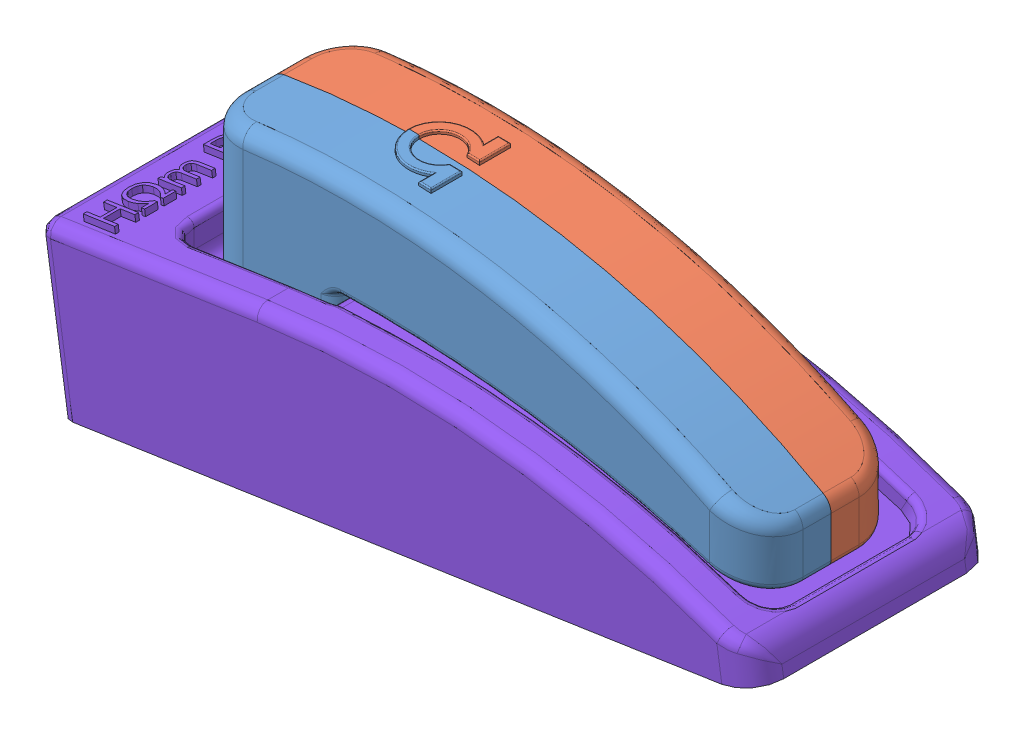
SolidWorks assembly final_assem, configuration Default. Lengths in mm.
Overall size (291.75 123.1 101.57).
10 component instances, 8 part files, 27 mates.
Components (placement in the parent):
- P8_right-1: P8_right [Default] at origin size (228.6 69.96 31.73)
- P8_left-1: P8_left [Default] at origin size (228.6 69.83 31.64)
- P1Speaker-1: P1Speaker [Default] at (29.1359 6.0917 30.5) x (0.999303 0.037323 0) z (-0.037323 0.999303 0) size (28 28 5.2)
- P1Inductor-1: P1Inductor [Default] at (29.0706 7.8405 30.5) x (0.999303 0.037323 0) z (0.037323 -0.999303 0) size (38.7 38.7 1.75)
- P1Keypad-2: P1Keypad [Default] at (121.818 36.3431 19.9085) x (0 0 1) z (-0.105093 -0.994462 0) size (51 64 15.68)
- button cap-1: button cap [Default] at (150.588 21.5839 47.6945) x (0.995909 -0.090357 0) z (0 0 1) size (10 5 10)
- button cap-2: button cap [Default] at (150.588 21.5839 24.3055) x (0.995909 -0.090357 0) z (0 0 1) size (10 5 10)
- led-1: led [Default] at (63.3042 28.0471 20.5) x (0.608948 -0.055249 -0.791284) z (-0.788047 0.071498 -0.611449) size (5 10.28 5)
- led-2: led [Default] at (63.3042 28.0471 40.5) x (-0.341202 0.030957 0.93948) z (0.935637 -0.084889 0.342604) size (5 10.28 5)
- Basepic-2: Basepic [Default] at (-2.8104 -2.6942 107.8186) x (1 0.000823 0) z (0 0 1) size (291.68 82.86 101.57)
Mates (geometry in assembly coordinates):
- Concentric1: concentric aligned: circle of P1Speaker-1; circle of P1Inductor-1
- Concentric2: concentric anti-aligned: circle of P8_right-1; circle of P1Speaker-1
- Coincident1: coincident: line of P8_right-1 through (36.7506 6.3761 31.5401) axis (0.999303 0.037323 0); plane of P1Inductor-1 through (29.1359 6.0917 30.5) normal (0.037323 -0.999303 0)
- Coincident2: coincident: line of P8_right-1 through (36.7506 6.3761 31.5401) axis (0.999303 0.037323 0); plane of P1Speaker-1 through (29.1359 6.0917 30.5) normal (0.037323 -0.999303 0)
- Concentric3: concentric aligned: cylinder of P8_right-1 through (6.35 55.6925 61) axis (0 0 -1) radius 6.35; cylinder of P8_left-1 through (6.35 55.6925 61) axis (0 0 -1) radius 6.35
- Concentric4: concentric aligned: cylinder of P8_right-1 through (226.06 1.7839 61) axis (0 0 -1) radius 2.54; cylinder of P8_left-1 through (226.06 1.7839 61) axis (0 0 -1) radius 2.54
- Coincident13: coincident: plane of P8_right-1 through (76.7043 40.1051 4.3119) normal (0.994462 -0.105093 0); line of P1Keypad-2 through (76.2839 36.1273 54.95) axis (0 0 -1)
- Coincident14: coincident: line of P8_right-1 through (138.2601 29.5777 30.5) axis (0.994462 -0.105093 0); plane of P1Keypad-2 through (121.2926 31.3708 19.9085) normal (-0.105093 -0.994462 0)
- Coincident15: coincident: line of P8_right-1 through (76.2839 36.1273 30.5) axis (0.994462 -0.105093 0); plane of P1Keypad-2 through (121.2926 31.3708 19.9085) normal (-0.105093 -0.994462 0)
- Coincident16: coincident: line of P8_right-1 through (81.5518 35.5706 54.6372) axis (0.994462 -0.105093 0.001005); plane of P1Keypad-2 through (121.2926 31.3708 19.9085) normal (-0.105093 -0.994462 0)
- Coincident17: coincident: plane of P8_right-1 through (0 -1.6705 30.5) normal (0 0 -1); moEndPointRef_w of P1Keypad-2
- Coincident18: coincident: plane of P8_right-1 through (0 -1.6705 30.5) normal (0 0 -1); moEndPointRef_w of P8_left-1
- Coincident19: coincident anti-aligned: plane of P8_right-1 through (151.1301 27.5593 47.6945) normal (0.995909 -0.090357 0); plane of button cap-1 through (151.0398 26.5634 47.6945) normal (-0.995909 0.090357 0)
- Coincident20: coincident anti-aligned: plane of P8_right-1 through (151.1301 27.5593 47.6945) normal (0 0 -1); plane of button cap-1 through (151.0398 26.5634 47.6945) normal (0 0 1)
- Distance1: distance = 2 mm aligned: plane of P8_right-1 through (3.3525 36.9505 0) normal (-0.090357 -0.995909 0); plane of button cap-1 through (150.588 21.5839 47.6945) normal (-0.090357 -0.995909 0)
- Coincident22: coincident anti-aligned: plane of P8_left-1 through (151.1301 27.5593 24.3055) normal (0 0 -1); plane of button cap-2 through (151.0398 26.5634 24.3055) normal (0 0 1)
- Coincident23: coincident anti-aligned: plane of P8_left-1 through (151.1301 27.5593 13.3055) normal (0.995909 -0.090357 0); plane of button cap-2 through (151.0398 26.5634 24.3055) normal (-0.995909 0.090357 0)
- Distance2: distance = 2 mm aligned: plane of button cap-2 through (150.588 21.5839 24.3055) normal (-0.090357 -0.995909 0); plane of P8_left-1 through (3.3525 36.9505 0) normal (-0.090357 -0.995909 0)
- Concentric5: concentric anti-aligned: cylinder of P8_left-1 through (60.1131 -7.1245 20.5) axis (0.090357 0.995909 0) radius 3; cylinder of led-1 through (63.0783 25.5573 20.5) axis (-0.090357 -0.995909 0) radius 2.5
- Tangent9: tangent anti-aligned: cylinder of P8_left-1 through (71.3027 -439.1129 61) axis (0 0 -1) radius 464.7284; sphere of led-1
- Concentric11: concentric anti-aligned: cylinder of P8_right-1 through (60.1131 -7.1245 40.5) axis (0.090357 0.995909 0) radius 3; cylinder of led-2 through (63.0783 25.5573 40.5) axis (-0.090357 -0.995909 0) radius 2.5
- Tangent10: tangent anti-aligned: cylinder of P8_right-1 through (71.3027 -439.1129 61) axis (0 0 -1) radius 464.7284; sphere of led-2
- Coincident26: coincident: plane of P8_right-1 through (0 -1.6705 30.5) normal (0 0 -1); moEndPointRef_w of Basepic-2
- Coincident27: coincident: plane of P8_right-1 through (0 -1.6705 30.5) normal (0 0 -1); moEndPointRef_w of Basepic-2
- Perpendicular1: perpendicular: plane of P8_right-1 through (0 -1.6705 30.5) normal (0 0 -1); plane of Basepic-2 through (55.4857 2.073 -3.5) normal (-0.038145 0.999272 0)
- Coincident29: coincident: point of P8_right-1; plane of Basepic-2 through (221.5624 0.441 -3.5) normal (0.27692 0.960893 0)
- Tangent12: tangent: circle of P8_right-1; plane of Basepic-2 through (55.4857 2.073 -3.5) normal (-0.038145 0.999272 0)
